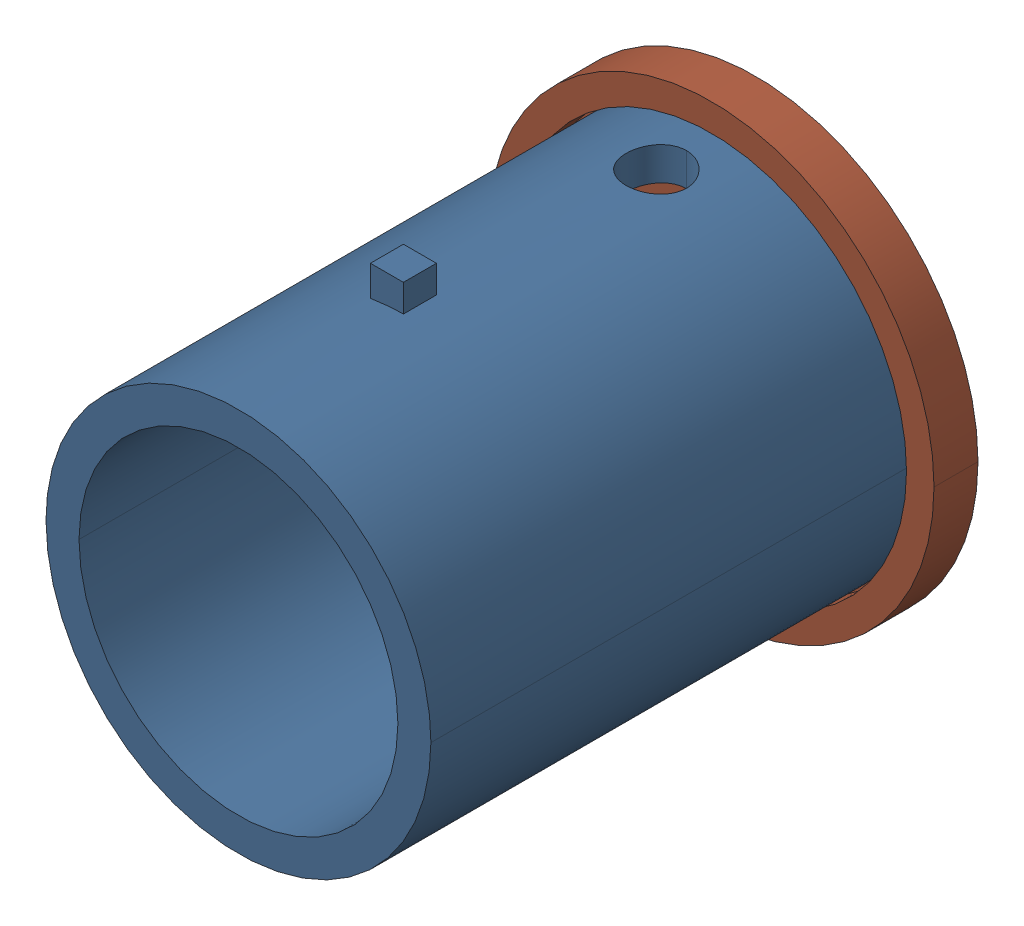
SolidWorks assembly Sensor_full, configuration Default. Lengths in mm.
Overall size (40.5 40.5 47).
23 component instances, 11 part files, 0 mates.
Components (placement in the parent):
- Sensor_full (1)^Sensor_full-1: Sensor_full (1)^Sensor_full [Default] at origin size (40.5 40.5 47) (virtual)
  - PCB_Sensor (2).step^Sensor_full (1)_Sensor_full-1: PCB_Sensor (2).step^Sensor_full (1)_Sensor_full [Default] at (36.1132 20.9634 32.6132) x (-0.923728 -0.383049 0) z (0 0 -1) size (28 28 15.12) (virtual)
    - Board.step^PCB_Sensor (2).step_Sensor_full (1)_Sensor_full-1: Board.step^PCB_Sensor (2).step_Sensor_full (1)_Sensor_full [Default] at origin size (28 28 0.41) (virtual)
      - Open CASCADE STEP translator 6.8 1.1.1.step^Board.step_PCB_Sensor (2).step_Sensor_full (1)_Sensor_full-1: Open CASCADE STEP translator 6.8 1.1.1.step^Board.step_PCB_Sensor (2).step_Sensor_full (1)_Sensor_full [Default] at (0 0 -0.4115) size (28 28 0.41) (virtual)
    - R7.step^PCB_Sensor (2).step_Sensor_full (1)_Sensor_full-1: R7.step^PCB_Sensor (2).step_Sensor_full (1)_Sensor_full [Default] at origin size (2.81 8.17 5.81) (virtual)
      - Resistor_10K_Ohm_tol1pct_0,25W__07,62.step^R7.step_PCB_Sensor (2).step_Sensor_full (1)_Sensor_full-1: Resistor_10K_Ohm_tol1pct_0,25W__07,62.step^R7.step_PCB_Sensor (2).step_Sensor_full (1)_Sensor_full [Default] at (25.5486 27.7914 1.8) x (1 0 0) z (0 0 1) size (2.81 8.17 5.81) (virtual)
    - D1.step^PCB_Sensor (2).step_Sensor_full (1)_Sensor_full-1: D1.step^PCB_Sensor (2).step_Sensor_full (1)_Sensor_full [Default] at origin size (5.93 5.41 12.16) (virtual)
      - LED_5mm_white_TH.step^D1.step_PCB_Sensor (2).step_Sensor_full (1)_Sensor_full-1: LED_5mm_white_TH.step^D1.step_PCB_Sensor (2).step_Sensor_full (1)_Sensor_full [Default] at (26.6701 17.6531 -2.8115) x (0 1 0) z (0 0 -1) size (5.41 5.93 12.16) (virtual)
    - R9.step^PCB_Sensor (2).step_Sensor_full (1)_Sensor_full-1: R9.step^PCB_Sensor (2).step_Sensor_full (1)_Sensor_full [Default] at origin size (4.88 4.17 9.64) (virtual)
      - 5044068176.step^R9.step_PCB_Sensor (2).step_Sensor_full (1)_Sensor_full-1: 5044068176.step^R9.step_PCB_Sensor (2).step_Sensor_full (1)_Sensor_full [Default] at (18.2815 22.1045 -9.0315) size (4.88 4.17 2.29) (virtual)
        - Extruded.step^5044068176.step_R9.step_PCB_Sensor (2).step_Sensor_full (1)_Sensor_full-1: Extruded.step^5044068176.step_R9.step_PCB_Sensor (2).step_Sensor_full (1)_Sensor_full [Default] at origin size (4.88 4.17 2.29) (virtual)
      - 6007015744.step^R9.step_PCB_Sensor (2).step_Sensor_full (1)_Sensor_full-1: 6007015744.step^R9.step_PCB_Sensor (2).step_Sensor_full (1)_Sensor_full [Default] at (19.553 22.1045 0.6125) x (-1 0 0) z (0 0 -1) size (0.76 0.76 7.87) (virtual)
        - Cylinder.step^6007015744.step_R9.step_PCB_Sensor (2).step_Sensor_full (1)_Sensor_full-1: Cylinder.step^6007015744.step_R9.step_PCB_Sensor (2).step_Sensor_full (1)_Sensor_full [Default] at origin size (0.76 0.76 7.87) (virtual)
      - 5044512256.step^R9.step_PCB_Sensor (2).step_Sensor_full (1)_Sensor_full-1: 5044512256.step^R9.step_PCB_Sensor (2).step_Sensor_full (1)_Sensor_full [Default] at (17.01 22.1045 0.6125) x (1 0 0) z (0 0 -1) size (0.76 0.76 7.87) (virtual)
        - Cylinder-0.step^5044512256.step_R9.step_PCB_Sensor (2).step_Sensor_full (1)_Sensor_full-1: Cylinder-0.step^5044512256.step_R9.step_PCB_Sensor (2).step_Sensor_full (1)_Sensor_full [Default] at origin size (0.76 0.76 7.87) (virtual)
    - R8.step^PCB_Sensor (2).step_Sensor_full (1)_Sensor_full-1: R8.step^PCB_Sensor (2).step_Sensor_full (1)_Sensor_full [Default] at origin size (2.81 8.17 5.81) (virtual)
      - Resistor_10K_Ohm_tol1pct_0,25W__07,62.step^R8.step_PCB_Sensor (2).step_Sensor_full (1)_Sensor_full-1: Resistor_10K_Ohm_tol1pct_0,25W__07,62.step^R8.step_PCB_Sensor (2).step_Sensor_full (1)_Sensor_full [Default] at (11.0491 27.6859 1.8) x (1 0 0) z (0 0 1) size (2.81 8.17 5.81) (virtual)
    - D3.step^PCB_Sensor (2).step_Sensor_full (1)_Sensor_full-1: D3.step^PCB_Sensor (2).step_Sensor_full (1)_Sensor_full [Default] at origin size (5.41 5.93 12.16) (virtual)
      - LED_5mm_white_TH.step^D3.step_PCB_Sensor (2).step_Sensor_full (1)_Sensor_full-1: LED_5mm_white_TH.step^D3.step_PCB_Sensor (2).step_Sensor_full (1)_Sensor_full [Default] at (18.2881 31.4959 -2.8115) x (1 0 0) z (0 0 -1) size (5.41 5.93 12.16) (virtual)
    - D2.step^PCB_Sensor (2).step_Sensor_full (1)_Sensor_full-1: D2.step^PCB_Sensor (2).step_Sensor_full (1)_Sensor_full [Default] at origin size (5.93 5.41 12.16) (virtual)
      - LED_5mm_white_TH.step^D2.step_PCB_Sensor (2).step_Sensor_full (1)_Sensor_full-1: LED_5mm_white_TH.step^D2.step_PCB_Sensor (2).step_Sensor_full (1)_Sensor_full [Default] at (9.9061 17.6531 -2.8115) x (0 1 0) z (0 0 -1) size (5.41 5.93 12.16) (virtual)
  - sensor_body^Sensor_full (1)_Sensor_full-1: sensor_body^Sensor_full (1)_Sensor_full [Default] at (10.7593 34.3799 30.3247) size (35 40 45) (virtual)
  - Sensor_Top^Sensor_full (1)_Sensor_full-1: Sensor_Top^Sensor_full (1)_Sensor_full [Default] at (10.7593 34.3799 18.3247) size (40.5 40.5 4) (virtual)
